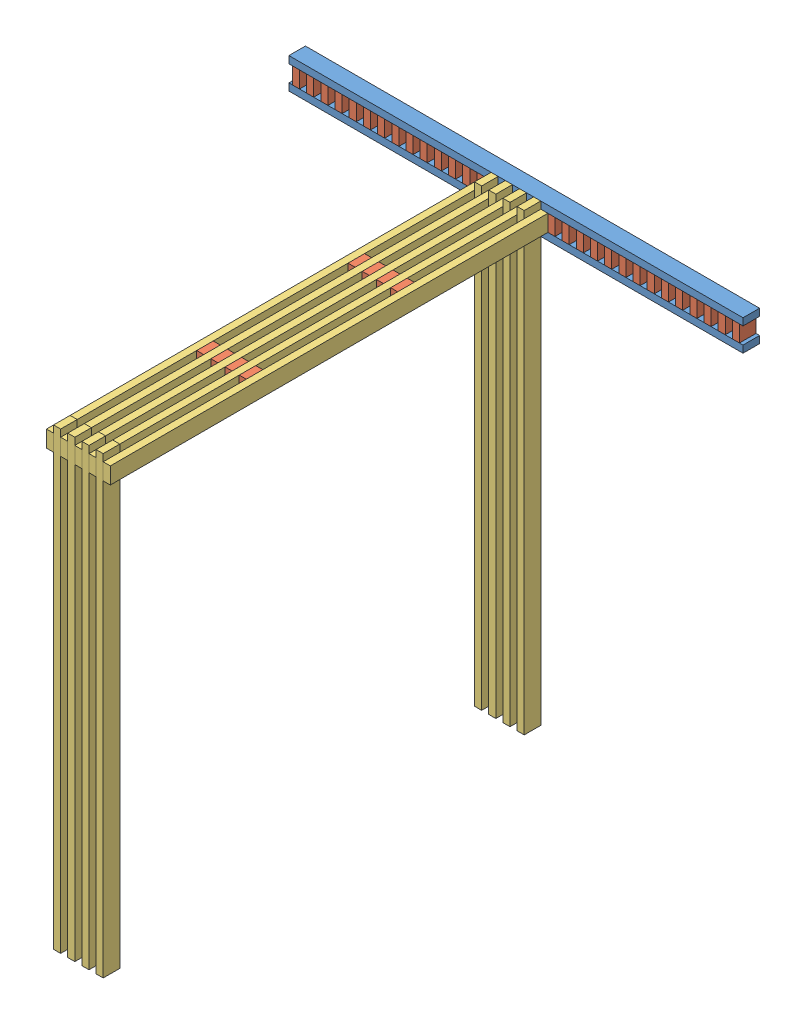
SolidWorks assembly truss, configuration Default. Lengths in mm.
Overall size (2438.4 2438.4 2438.4).
62 component instances, 3 part files, 12 mates.
Components (placement in the parent):
- foot_plus_side_post-1: foot_plus_side_post [Default] at (-927.419 -1332.037 -3654.4904) size (2438.4 165.1 2438.4)
  - foot_post-1: foot_post [Default] at (1347.1514 1068.5792 1779.6361) size (2438.4 165.1 88.9)
    - 2x4_foot-1: 2x4_foot [Default] at (-704.8006 1778.2043 2380.3143) size (2438.4 38.1 88.9)
    - 2x4_foot-2: 2x4_foot [Default] at (-704.8006 1689.3043 2469.2143) x (1 0 0) z (0 0 -1) size (2438.4 38.1 88.9)
    - 4x4x2_gusset-32: 4x4x2_gusset [Default] at (571.5494 1689.3043 2380.3143) x (0 1 0) z (0 0 1) size (88.9 38.1 88.9)
    - 4x4x2_gusset-33: 4x4x2_gusset [Default] at (495.3494 1689.3043 2380.3143) x (0 1 0) z (0 0 1) size (88.9 38.1 88.9)
    - 4x4x2_gusset-34: 4x4x2_gusset [Default] at (419.1494 1689.3043 2380.3143) x (0 1 0) z (0 0 1) size (88.9 38.1 88.9)
    - 4x4x2_gusset-35: 4x4x2_gusset [Default] at (342.9494 1689.3043 2380.3143) x (0 1 0) z (0 0 1) size (88.9 38.1 88.9)
    - 4x4x2_gusset-36: 4x4x2_gusset [Default] at (266.7494 1689.3043 2380.3143) x (0 1 0) z (0 0 1) size (88.9 38.1 88.9)
    - 4x4x2_gusset-37: 4x4x2_gusset [Default] at (190.5494 1689.3043 2380.3143) x (0 1 0) z (0 0 1) size (88.9 38.1 88.9)
    - 4x4x2_gusset-38: 4x4x2_gusset [Default] at (114.3494 1689.3043 2380.3143) x (0 1 0) z (0 0 1) size (88.9 38.1 88.9)
    - 4x4x2_gusset-39: 4x4x2_gusset [Default] at (38.1494 1689.3043 2380.3143) x (0 1 0) z (0 0 1) size (88.9 38.1 88.9)
    - 4x4x2_gusset-40: 4x4x2_gusset [Default] at (-38.0506 1689.3043 2380.3143) x (0 1 0) z (0 0 1) size (88.9 38.1 88.9)
    - 4x4x2_gusset-41: 4x4x2_gusset [Default] at (-114.2506 1689.3043 2380.3143) x (0 1 0) z (0 0 1) size (88.9 38.1 88.9)
    - 4x4x2_gusset-42: 4x4x2_gusset [Default] at (-190.4506 1689.3043 2380.3143) x (0 1 0) z (0 0 1) size (88.9 38.1 88.9)
    - 4x4x2_gusset-43: 4x4x2_gusset [Default] at (-266.6506 1689.3043 2380.3143) x (0 1 0) z (0 0 1) size (88.9 38.1 88.9)
    - 4x4x2_gusset-44: 4x4x2_gusset [Default] at (-342.8506 1689.3043 2380.3143) x (0 1 0) z (0 0 1) size (88.9 38.1 88.9)
    - 4x4x2_gusset-45: 4x4x2_gusset [Default] at (-419.0506 1689.3043 2380.3143) x (0 1 0) z (0 0 1) size (88.9 38.1 88.9)
    - 4x4x2_gusset-46: 4x4x2_gusset [Default] at (-495.2506 1689.3043 2380.3143) x (0 1 0) z (0 0 1) size (88.9 38.1 88.9)
    - 4x4x2_gusset-47: 4x4x2_gusset [Default] at (-571.4506 1689.3043 2380.3143) x (0 1 0) z (0 0 1) size (88.9 38.1 88.9)
    - 4x4x2_gusset-48: 4x4x2_gusset [Default] at (-647.6506 1689.3043 2380.3143) x (0 1 0) z (0 0 1) size (88.9 38.1 88.9)
    - 4x4x2_gusset-49: 4x4x2_gusset [Default] at (647.7494 1689.3043 2380.3143) x (0 1 0) z (0 0 1) size (88.9 38.1 88.9)
    - 4x4x2_gusset-50: 4x4x2_gusset [Default] at (723.9494 1689.3043 2380.3143) x (0 1 0) z (0 0 1) size (88.9 38.1 88.9)
    - 4x4x2_gusset-51: 4x4x2_gusset [Default] at (800.1494 1689.3043 2380.3143) x (0 1 0) z (0 0 1) size (88.9 38.1 88.9)
    - 4x4x2_gusset-52: 4x4x2_gusset [Default] at (876.3494 1689.3043 2380.3143) x (0 1 0) z (0 0 1) size (88.9 38.1 88.9)
    - 4x4x2_gusset-53: 4x4x2_gusset [Default] at (952.5494 1689.3043 2380.3143) x (0 1 0) z (0 0 1) size (88.9 38.1 88.9)
    - 4x4x2_gusset-54: 4x4x2_gusset [Default] at (1028.7494 1689.3043 2380.3143) x (0 1 0) z (0 0 1) size (88.9 38.1 88.9)
    - 4x4x2_gusset-55: 4x4x2_gusset [Default] at (1104.9494 1689.3043 2380.3143) x (0 1 0) z (0 0 1) size (88.9 38.1 88.9)
    - 4x4x2_gusset-56: 4x4x2_gusset [Default] at (1181.1494 1689.3043 2380.3143) x (0 1 0) z (0 0 1) size (88.9 38.1 88.9)
    - 4x4x2_gusset-57: 4x4x2_gusset [Default] at (1257.3494 1689.3043 2380.3143) x (0 1 0) z (0 0 1) size (88.9 38.1 88.9)
    - 4x4x2_gusset-58: 4x4x2_gusset [Default] at (1333.5494 1689.3043 2380.3143) x (0 1 0) z (0 0 1) size (88.9 38.1 88.9)
    - 4x4x2_gusset-59: 4x4x2_gusset [Default] at (1409.7494 1689.3043 2380.3143) x (0 1 0) z (0 0 1) size (88.9 38.1 88.9)
    - 4x4x2_gusset-60: 4x4x2_gusset [Default] at (1485.9494 1689.3043 2380.3143) x (0 1 0) z (0 0 1) size (88.9 38.1 88.9)
    - 4x4x2_gusset-61: 4x4x2_gusset [Default] at (1562.1494 1689.3043 2380.3143) x (0 1 0) z (0 0 1) size (88.9 38.1 88.9)
    - 4x4x2_gusset-62: 4x4x2_gusset [Default] at (1638.3494 1689.3043 2380.3143) x (0 1 0) z (0 0 1) size (88.9 38.1 88.9)
    - 4x4x2_gusset-63: 4x4x2_gusset [Default] at (1714.5494 1689.3043 2380.3143) x (0 1 0) z (0 0 1) size (88.9 38.1 88.9)
  - 18x4_female_post-1: 18x4_female_post [Default] at (4665.928 6948.7926 3132.4615) x (0 0 1) z (0 -1 0) size (2438.4 342.9 88.9)
    - 6x4_female_post-1: 6x4_female_post [Default] at (1617.4053 951.3945 1716.6403) size (2438.4 114.3 88.9)
      - 2x4-1: 2x4 [Default] at (-589.9165 1681.5327 2385.3688) size (2438.4 38.1 88.9)
      - 4x4x2_gusset-1: 4x4x2_gusset [Default] at (178.4335 1719.6327 2385.3688) size (88.9 38.1 88.9)
      - 4x4x2_gusset-2: 4x4x2_gusset [Default] at (991.2335 1719.6327 2385.3688) size (88.9 38.1 88.9)
      - 2x4-2: 2x4 [Default] at (-589.9165 1757.7327 2385.3688) size (2438.4 38.1 88.9)
    - 6x4_female_post-2: 6x4_female_post [Default] at (1617.4053 1103.7945 1716.6403) size (2438.4 114.3 88.9)
      - 2x4-1: 2x4 [Default] at (-589.9165 1681.5327 2385.3688) size (2438.4 38.1 88.9)
      - 4x4x2_gusset-1: 4x4x2_gusset [Default] at (178.4335 1719.6327 2385.3688) size (88.9 38.1 88.9)
      - 4x4x2_gusset-2: 4x4x2_gusset [Default] at (991.2335 1719.6327 2385.3688) size (88.9 38.1 88.9)
      - 2x4-2: 2x4 [Default] at (-589.9165 1757.7327 2385.3688) size (2438.4 38.1 88.9)
    - 4x4x2_gusset-1: 4x4x2_gusset [Default] at (1795.8388 2747.2272 4102.0091) size (88.9 38.1 88.9)
    - 4x4x2_gusset-2: 4x4x2_gusset [Default] at (2608.6388 2747.2272 4102.0091) size (88.9 38.1 88.9)
    - 2x4-1: 2x4 [Default] at (1027.4888 2937.7272 4102.0091) size (2438.4 38.1 88.9)
    - 4x4x2_gusset-3: 4x4x2_gusset [Default] at (1795.8388 2899.6272 4102.0091) size (88.9 38.1 88.9)
    - 4x4x2_gusset-4: 4x4x2_gusset [Default] at (2608.6388 2899.6272 4102.0091) size (88.9 38.1 88.9)
- truss_beam-1: truss_beam [Default] at (-539.4757 988.8329 -1308.4501) x (0 -1 0) z (0 0 1) size (2438.4 266.7 88.9)
  - 2x4-1: 2x4 [Default] at (-564.0137 1340.2575 1902.8101) size (2438.4 38.1 88.9)
  - 2x4-2: 2x4 [Default] at (-564.0137 1416.4575 1902.8101) size (2438.4 38.1 88.9)
  - 2x4-3: 2x4 [Default] at (-564.0137 1492.6575 1902.8101) size (2438.4 38.1 88.9)
  - 2x4-4: 2x4 [Default] at (-564.0137 1568.8575 1902.8101) size (2438.4 38.1 88.9)
- truss_beam-2: truss_beam [Default] at (2407.7393 -321.5397 952.1499) x (0 1 0) z (0 0 1) size (2438.4 266.7 88.9)
  - 2x4-1: 2x4 [Default] at (-564.0137 1340.2575 1902.8101) size (2438.4 38.1 88.9)
  - 2x4-2: 2x4 [Default] at (-564.0137 1416.4575 1902.8101) size (2438.4 38.1 88.9)
  - 2x4-3: 2x4 [Default] at (-564.0137 1492.6575 1902.8101) size (2438.4 38.1 88.9)
  - 2x4-4: 2x4 [Default] at (-564.0137 1568.8575 1902.8101) size (2438.4 38.1 88.9)
Mates (geometry in assembly coordinates):
- Coincident1: coincident: plane of ? through (838.8818 1514.7466 505.46) normal (1 0 0); plane of ? through (838.8818 1552.8466 594.36) normal (-1 0 0)
- Coincident2: coincident: plane of foot_plus_side_post-1/foot_post-1/2x4_foot-1 through (-285.0682 1552.8466 594.36) normal (0 0 1); plane of ? through (876.9818 1552.8466 594.36) normal (0 0 -1)
- Coincident3: coincident: plane of foot_plus_side_post-1/foot_post-1/2x4_foot-1 through (-285.0682 1552.8466 505.46) normal (0 1 0); plane of ? through (876.9818 1552.8466 594.36) normal (0 1 0)
- Coincident4: coincident: plane of foot_plus_side_post-1/18x4_female_post-1/2x4-1 through (800.7818 1514.7466 505.46) normal (1 0 0); plane of truss_beam-1/2x4-1 through (800.7818 1552.8466 594.36) normal (-1 0 0)
- Coincident5: coincident: plane of foot_plus_side_post-1/foot_post-1/2x4_foot-2 through (-285.0682 1387.7466 594.36) normal (0 0 1); plane of truss_beam-1/2x4-1 through (838.8818 1552.8466 594.36) normal (0 0 -1)
- Coincident6: coincident: plane of foot_plus_side_post-1/foot_post-1/2x4_foot-1 through (-285.0682 1552.8466 505.46) normal (0 1 0); plane of truss_beam-1/2x4-1 through (838.8818 1552.8466 594.36) normal (0 1 0)
- Coincident7: coincident: plane of foot_plus_side_post-1/18x4_female_post-1/2x4-1 through (800.7818 1514.7466 505.46) normal (1 0 0); plane of truss_beam-1/2x4-1 through (800.7818 1552.8466 594.36) normal (-1 0 0)
- Coincident8: coincident: plane of foot_plus_side_post-1/foot_post-1/2x4_foot-1 through (-285.0682 1552.8466 505.46) normal (0 1 0); plane of truss_beam-1/2x4-1 through (838.8818 1552.8466 594.36) normal (0 1 0)
- Coincident9: coincident: plane of foot_plus_side_post-1/foot_post-1/2x4_foot-1 through (-285.0682 1552.8466 594.36) normal (0 0 1); plane of truss_beam-1/2x4-1 through (838.8818 1552.8466 594.36) normal (0 0 -1)
- Coincident11: coincident: plane of foot_plus_side_post-1/18x4_female_post-1/2x4-1 through (800.7818 1514.7466 505.46) normal (1 0 0); plane of truss_beam-2/2x4-4 through (800.7818 -885.5534 2854.96) normal (-1 0 0)
- Coincident13: coincident: plane of truss_beam-1/2x4-1 through (838.8818 1552.8466 594.36) normal (0 1 0); plane of truss_beam-2/2x4-4 through (800.7818 1552.8466 2854.96) normal (0 1 0)
- Coincident14: coincident: plane of foot_plus_side_post-1/18x4_female_post-1/2x4-1 through (762.6818 1514.7466 2943.86) normal (0 0 1); plane of truss_beam-2/2x4-4 through (800.7818 -885.5534 2943.86) normal (0 0 1)
